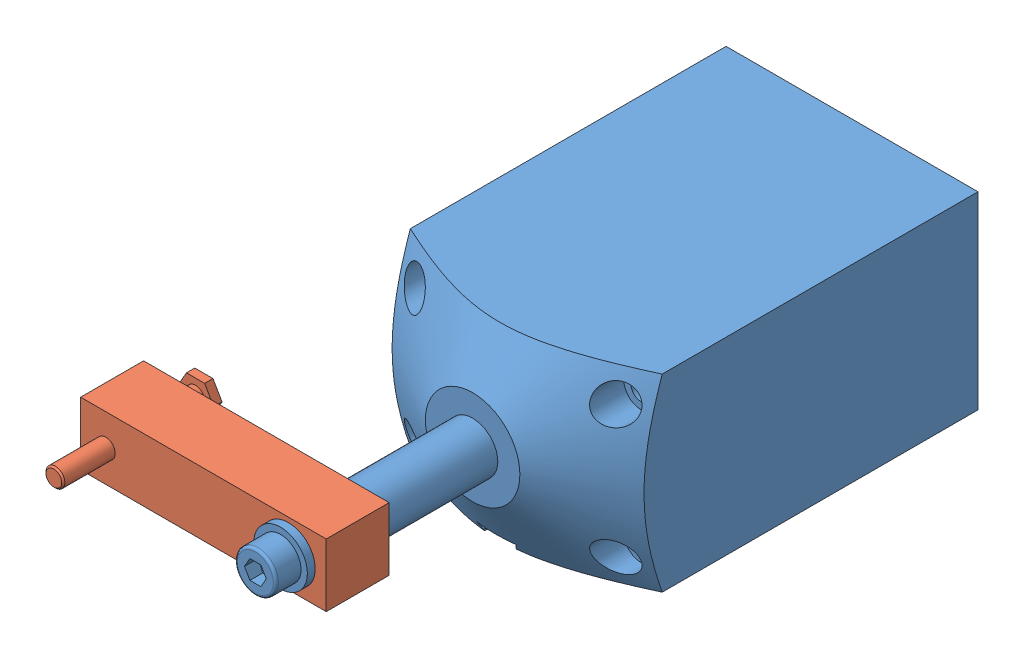
SolidWorks assembly Subconjunto Aperto 1875106CW, configuration Default. Lengths in mm.
Overall size (106.05 79.39 195.5).
2 component instances, 2 part files, 3 mates.
Components (placement in the parent):
- 1875106BCW.stp-1: 1875106BCW.stp [Default] at (0.7105 124.0841 246.4327) size (80.1 79.39 189.5)
- 0187526.stp-3: 0187526.stp [Default] at (0.7105 124.0841 235.9327) x (-1 0 0) z (0 0 1) size (78 20 47.65)
Mates (geometry in assembly coordinates):
- Concentric1: concentric anti-aligned: cylinder of 1875106BCW.stp-1 through (0.7105 124.0841 176.454) axis (0 0 -1) radius 8; cone of 0187526.stp-3 through (0.7105 124.0841 235.9327) axis (0 0 1)
- Coincident1: coincident aligned: circle of 1875106BCW.stp-1; plane of 0187526.stp-3 through (12.7105 134.0841 215.9327) normal (0 0 -1)
- LimitAngle1: limit planar angle = 0 rad aligned: plane of 1875106BCW.stp-1 through (-39.2895 94.0841 56.9327) normal (-1 0 0); plane of 0187526.stp-3 through (-65.2895 114.0841 215.9327) normal (-1 0 0)
